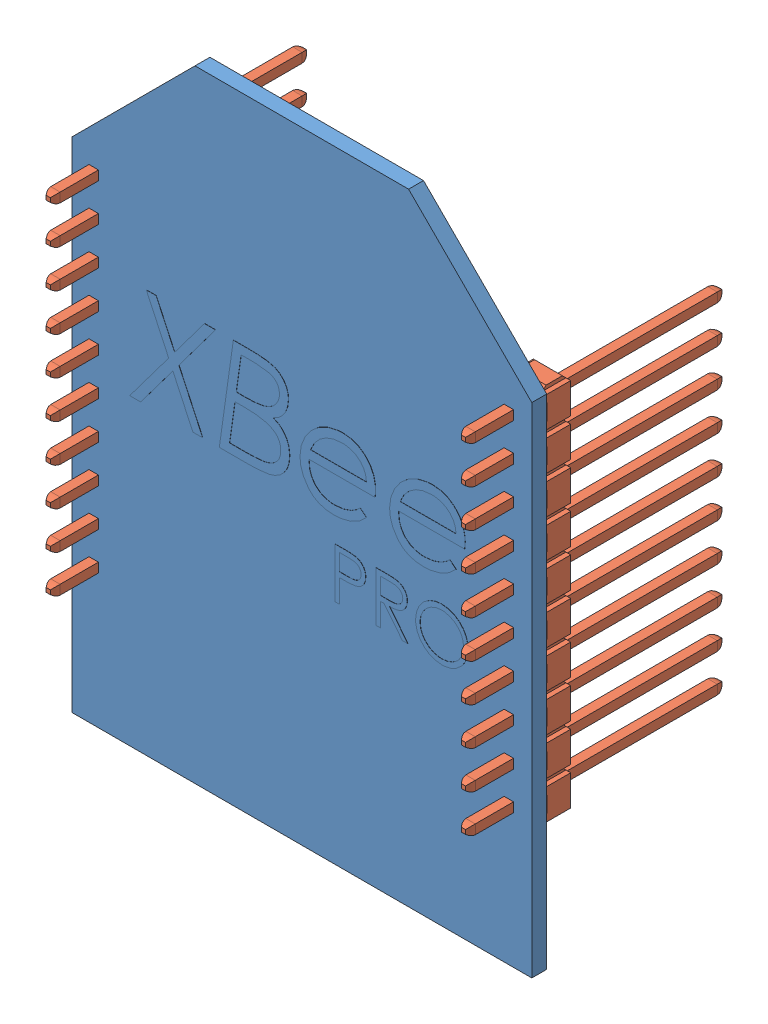
SolidWorks assembly XBEE Pro, configuration Défaut. Lengths in mm.
Overall size (24.38 32.94 13.59).
3 component instances, 2 part files, 4 mates.
Components (placement in the parent):
- XBEE PCB-1: XBEE PCB [Défaut] at origin size (24.38 32.94 0.8)
- MTMM-106-09-X-S-350-1: MTMM-106-09-X-S-350 [Défaut] at (-9.8374 3.8829 -0.8763) x (0 1 0) z (-1 0 0) size (20 13.59 1.98)
- MTMM-106-09-X-S-350-2: MTMM-106-09-X-S-350 [Défaut] at (12.1626 3.8829 -0.8763) x (0 1 0) z (-1 0 0) size (20 13.59 1.98)
Mates (geometry in assembly coordinates):
- Coïncidente1: coincident anti-aligned: plane of XBEE PCB-1 through (13.38 -16.47 0) normal (0 0 -1); plane of MTMM-106-09-X-S-350-1 through (-10.447 9.3114 0) normal (0 0 1)
- Coïncidente2: coincident anti-aligned: plane of XBEE PCB-1 through (13.38 -16.47 0) normal (0 0 -1); plane of MTMM-106-09-X-S-350-2 through (11.553 0.4544 0) normal (0 0 1)
- Distance1: distance = 22 mm: line of MTMM-106-09-X-S-350-1; line of MTMM-106-09-X-S-350-2
- Coïncidente4: coincident aligned: line of MTMM-106-09-X-S-350-1; line of MTMM-106-09-X-S-350-2
